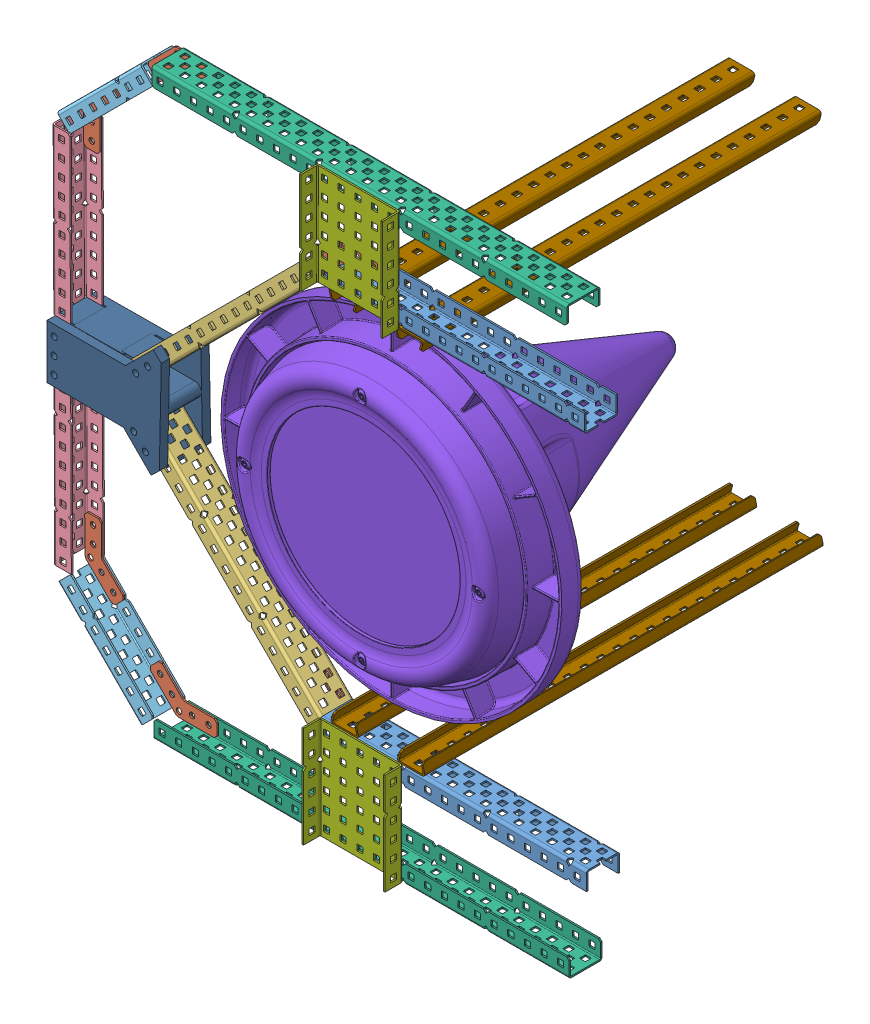
SolidWorks assembly Assem1, configuration Default. Lengths in mm.
Overall size (422.2 445.54 318.67).
23 component instances, 10 part files, 69 mates.
Components (placement in the parent):
- Channel 121-25 Aluminum-1: Channel 121-25 Aluminum [Default] at (-71.4802 130.2056 305.0856) size (203.98 13.87 25.4)
- 45 Degree Gusset Steel-1: 45 Degree Gusset Steel [Default] at (-111.3904 134.6957 291.8218) x (0.707107 0.707107 0) z (-0.707107 0.707107 0) size (29.13 1.17 50.81)
- Channel 121-15 Steel-1: Channel 121-15 Steel [Default] at (-213.9281 246.2136 305.0856) x (0.707107 -0.707107 0) z (0 0 1) size (190.5 13.87 25.4)
- Channel 121-25 Aluminum-5: Channel 121-25 Aluminum [Default] at (-72.9903 421.0087 299.2845) x (1 0 0) z (0 0 -1) size (203.98 13.87 25.4)
- 45 Degree Gusset Steel-11: 45 Degree Gusset Steel [Default] at (-112.9005 416.5439 290.6534) x (0.707107 -0.707107 0) z (-0.707107 -0.707107 0) size (29.13 1.17 50.81)
- Channel 121-15 Steel-5: Channel 121-15 Steel [Default] at (-215.4562 305.044 299.2845) x (0.707107 0.707107 0) z (0 0 -1) size (190.5 13.87 25.4)
- 45 Degree Gusset Steel-13: 45 Degree Gusset Steel [Default] at (-283.5405 116.115 290.6534) x (0.704273 0.70993 0) z (0.70993 -0.704273 0) size (29.13 1.17 50.81)
- 45 Degree Gusset Steel-14: 45 Degree Gusset Steel [Default] at (-284.8166 435.1532 291.8218) x (0.70993 -0.704273 0) z (0.704273 0.70993 0) size (29.13 1.17 50.81)
- Channel 121-23 Aluminum-1: Channel 121-23 Aluminum [Default] at (-300.7631 130.5564 305.0856) x (-0.004 0.999992 0) z (0 0 1) size (291.03 13.87 25.4)
- Channel 121-7 Aluminum-1: Channel 121-7 Aluminum [Default] at (-279.5913 449.3588 305.0856) x (0.707107 0.707107 0) z (0 0 1) size (89.86 13.87 25.4)
- Channel 121-7 Aluminum-4: Channel 121-7 Aluminum [Default] at (-252.8448 76.4391 305.0856) x (-0.707107 0.707107 0) z (0 0 1) size (89.86 13.87 25.4)
- 45 Degree Gusset Steel-15: 45 Degree Gusset Steel [Default] at (-212.4867 60.3556 290.6534) x (0 1 0) z (1 0 0) size (29.13 1.17 50.81)
- Channel 121-25 Al-1: Channel 121-25 Al [Default] at (66.0894 54.0056 305.0856) x (-1 0 0) z (0 0 1) size (317.5 13.87 25.4)
- Channel 121-25 Al-3: Channel 121-25 Al [Default] at (64.5793 497.2087 299.2845) x (-1 0 0) z (0 0 -1) size (317.5 13.87 25.4)
- 45 Degree Gusset Steel-17: 45 Degree Gusset Steel [Default] at (-213.7809 490.8587 291.8218) x (0 -1 0) z (1 0 0) size (29.13 1.17 50.81)
- Channel 151-6 Steel-1: Channel 151-6 Steel [Default] at (-82.0909 141.8404 316.0534) x (0 -1 0) z (1 0 0) size (77.37 13.87 63.5)
- Channel 151-6 Steel-2: Channel 151-6 Steel [Default] at (-51.8101 409.3739 316.0534) x (0 1 0) z (-1 0 0) size (77.37 13.87 63.5)
- mobileGoalPart-1: mobileGoalPart [Default] at (-61.7017 276.3928 324.2446) x (0.999695 0 -0.024681) z (0 1 0) size (254.67 244.72 254.67)
- rail-1: rail [Default] at (-78.8954 131.374 162.485) x (1 0 0) z (0 1 0) size (20.84 304.8 8.8)
- rail-2: rail [Default] at (-28.0954 131.374 162.485) x (1 0 0) z (0 1 0) size (20.84 304.8 8.8)
- rail-4: rail [Default] at (-29.6055 419.7384 162.485) x (-1 0 0) z (0 -1 0) size (20.84 304.8 8.8)
- rail-5: rail [Default] at (-80.4055 419.8403 162.485) x (-1 0 0) z (0 -1 0) size (20.84 304.8 8.8)
- Rear Frame Support^Assem1-1: Rear Frame Support^Assem1 [Default] at origin size (87.73 84.38 38.1) (virtual)
Mates (geometry in assembly coordinates):
- Coincident2: coincident anti-aligned: plane of Channel 121-25 Aluminum-1 through (-97.9454 130.2056 314.885) normal (0 -1 0); plane of 45 Degree Gusset Steel-1 through (-72.52 130.2056 290.6534) normal (0 1 0)
- Coincident3: coincident anti-aligned: plane of Channel 121-25 Aluminum-1 through (-97.9454 130.2056 290.6534) normal (0 0 1); plane of 45 Degree Gusset Steel-1 through (-124.8608 139.1858 290.6534) normal (0 0 -1)
- Distance1: distance = 2.286 mm: cylinder of 45 Degree Gusset Steel-1 through (-78.87 123.8556 290.6534) axis (0 0 1) radius 2.0701; plane of Channel 121-25 Aluminum-1 through (-76.584 126.167 289.485) normal (-1 0 0)
- Coincident7: coincident anti-aligned: plane of 45 Degree Gusset Steel-1 through (-97.92 130.2056 290.6534) normal (0.707107 0.707107 0); plane of Channel 121-15 Steel-1 through (-232.6418 264.9274 314.885) normal (-0.707107 -0.707107 0)
- Coincident8: coincident anti-aligned: plane of 45 Degree Gusset Steel-1 through (-124.8608 139.1858 290.6534) normal (0 0 -1); plane of Channel 121-15 Steel-1 through (-232.6418 264.9274 290.6534) normal (0 0 1)
- Distance2: distance = 2.286 mm: plane of Channel 121-15 Steel-1 through (-103.6494 130.2235 289.485) normal (-0.707107 0.707107 0); cylinder of 45 Degree Gusset Steel-1 through (-106.9003 130.2056 290.6534) axis (0 0 1) radius 2.0701
- Distance22: distance = 2.286 mm: cylinder of 45 Degree Gusset Steel-11 through (-117.3906 412.0538 291.8218) axis (0 0 -1) radius 2.0701; plane of Channel 121-15 Steel-5 through (-114.1577 412.0538 314.885) normal (-0.707107 -0.707107 0)
- Distance23: distance = 2.286 mm: cylinder of 45 Degree Gusset Steel-11 through (-117.3906 412.0538 291.8218) axis (0 0 -1) radius 2.0701; plane of Channel 121-15 Steel-5 through (-117.4266 408.785 314.885) normal (-0.707107 0.707107 0)
- Coincident40: coincident anti-aligned: plane of 45 Degree Gusset Steel-11 through (-126.3709 412.0538 290.6534) normal (0 0 -1); plane of Channel 121-15 Steel-5 through (-234.1699 286.3302 290.6534) normal (0 0 1)
- Coincident41: coincident anti-aligned: plane of Channel 121-25 Aluminum-5 through (-99.4555 421.0087 290.6534) normal (0 0 1); plane of 45 Degree Gusset Steel-11 through (-126.3709 412.0538 290.6534) normal (0 0 -1)
- Distance24: distance = 2.286 mm: plane of Channel 121-25 Aluminum-5 through (-78.0941 425.0473 314.885) normal (-1 0 0); cylinder of 45 Degree Gusset Steel-11 through (-80.3801 427.3841 291.8218) axis (0 0 -1) radius 2.0701
- Distance25: distance = 2.286 mm: cylinder of 45 Degree Gusset Steel-11 through (-80.3801 427.3841 291.8218) axis (0 0 -1) radius 2.0701; plane of Channel 121-25 Aluminum-5 through (-82.7169 429.6701 314.885) normal (0 -1 0)
- Distance26: distance = 2.286 mm: cylinder of 45 Degree Gusset Steel-13 through (-294.5106 148.5918 291.8218) axis (0 0 -1) radius 2.0701; plane of Channel 121-23 Aluminum-1 through (-296.7872 146.2458 289.485) normal (0.999992 0.004 0)
- Coincident48: coincident anti-aligned: plane of 45 Degree Gusset Steel-13 through (-278.9965 102.6627 290.6534) normal (0 0 -1); plane of Channel 121-23 Aluminum-1 through (-300.6572 104.0914 290.6534) normal (0 0 1)
- Parallel2: parallel anti-aligned: plane of 45 Degree Gusset Steel-13 through (-300.768 125.4245 291.8218) normal (-0.999992 -0.004 0); plane of Channel 121-23 Aluminum-1 through (-300.6572 104.0914 314.885) normal (0.999992 0.004 0)
- Distance27: distance = 2.286 mm: plane of Channel 121-23 Aluminum-1 through (-296.8057 150.8686 289.485) normal (0.004 -0.999992 0); cylinder of 45 Degree Gusset Steel-13 through (-294.5106 148.5918 291.8218) axis (0 0 -1) radius 2.0701
- Distance33: distance = 2.286 mm: cylinder of 45 Degree Gusset Steel-11 through (-108.4104 421.0341 291.8218) axis (0 0 -1) radius 2.0701; plane of Channel 121-15 Steel-5 through (-105.1775 421.0341 314.885) normal (-0.707107 -0.707107 0)
- Distance34: distance = 2.286 mm: plane of Channel 121-25 Aluminum-5 through (-90.7941 425.0473 314.885) normal (-1 0 0); cylinder of 45 Degree Gusset Steel-11 through (-93.0801 427.3841 291.8218) axis (0 0 -1) radius 2.0701
- Coincident54: coincident anti-aligned: plane of 45 Degree Gusset Steel-14 through (-280.3804 448.6414 290.6534) normal (0 0 -1); plane of Channel 121-23 Aluminum-1 through (-300.6572 104.0914 290.6534) normal (0 0 1)
- Distance36: distance = 2.286 mm: plane of Channel 121-23 Aluminum-1 through (-297.8032 400.2438 289.485) normal (0.999992 0.004 0); cylinder of 45 Degree Gusset Steel-14 through (-295.5266 402.5897 290.6534) axis (0 0 1) radius 2.0701
- Distance37: distance = 2.286 mm: cylinder of 45 Degree Gusset Steel-14 through (-295.5266 402.5897 290.6534) axis (0 0 1) radius 2.0701; plane of Channel 121-23 Aluminum-1 through (-297.8217 404.8666 289.485) normal (0.004 -0.999992 0)
- Distance40: distance = 2.286 mm: cylinder of 45 Degree Gusset Steel-14 through (-295.5774 415.2896 290.6534) axis (0 0 1) radius 2.0701; plane of Channel 121-23 Aluminum-1 through (-297.854 412.9437 289.485) normal (0.999992 0.004 0)
- Coincident55: coincident anti-aligned: plane of 45 Degree Gusset Steel-14 through (-280.3804 448.6414 290.6534) normal (0 0 -1); plane of Channel 121-7 Aluminum-1 through (-298.305 430.6451 290.6534) normal (0 0 1)
- Distance42: distance = 2.286 mm: plane of Channel 121-7 Aluminum-1 through (-283.6133 439.6253 289.485) normal (0.707107 -0.707107 0); cylinder of 45 Degree Gusset Steel-14 through (-280.3445 439.6613 290.6534) axis (0 0 1) radius 2.0701
- Distance43: distance = 2.286 mm: plane of Channel 121-7 Aluminum-1 through (-280.3445 442.8941 289.485) normal (-0.707107 -0.707107 0); cylinder of 45 Degree Gusset Steel-14 through (-280.3445 439.6613 290.6534) axis (0 0 1) radius 2.0701
- Distance45: distance = 2.286 mm: plane of Channel 121-7 Aluminum-1 through (-289.3248 427.3763 289.485) normal (-0.707107 0.707107 0); cylinder of 45 Degree Gusset Steel-14 through (-289.2888 430.6452 290.6534) axis (0 0 1) radius 2.0701
- Coincident58: coincident anti-aligned: plane of 45 Degree Gusset Steel-13 through (-278.9965 102.6627 290.6534) normal (0 0 -1); plane of Channel 121-7 Aluminum-4 through (-234.1311 57.7253 290.6534) normal (0 0 1)
- Distance55: distance = 2.286 mm: plane of Channel 121-7 Aluminum-4 through (-288.0126 117.3183 289.485) normal (0.707107 0.707107 0); cylinder of 45 Degree Gusset Steel-13 through (-288.0485 120.5871 291.8218) axis (0 0 -1) radius 2.0701
- Distance56: distance = 2.286 mm: plane of Channel 121-7 Aluminum-4 through (-291.2814 120.5871 289.485) normal (0.707107 -0.707107 0); cylinder of 45 Degree Gusset Steel-13 through (-288.0485 120.5871 291.8218) axis (0 0 -1) radius 2.0701
- Distance57: distance = 2.286 mm: cylinder of 45 Degree Gusset Steel-13 through (-279.0324 111.6429 291.8218) axis (0 0 -1) radius 2.0701; plane of Channel 121-7 Aluminum-4 through (-275.7635 111.6069 289.485) normal (-0.707107 -0.707107 0)
- Coincident61: coincident anti-aligned: plane of Channel 121-7 Aluminum-4 through (-234.1311 57.7253 290.6534) normal (0 0 1); plane of 45 Degree Gusset Steel-15 through (-199.7867 54.0056 290.6534) normal (0 0 -1)
- Distance58: distance = 2.286 mm: cylinder of 45 Degree Gusset Steel-15 through (-243.1472 75.6858 291.8218) axis (0 0 -1) radius 2.0701; plane of Channel 121-7 Aluminum-4 through (-246.3801 75.6858 289.485) normal (0.707107 -0.707107 0)
- Distance60: distance = 2.286 mm: plane of Channel 121-7 Aluminum-4 through (-243.1113 72.417 289.485) normal (0.707107 0.707107 0); cylinder of 45 Degree Gusset Steel-15 through (-243.1472 75.6858 291.8218) axis (0 0 -1) radius 2.0701
- Distance61: distance = 2.286 mm: cylinder of 45 Degree Gusset Steel-15 through (-234.167 66.7056 291.8218) axis (0 0 -1) radius 2.0701; plane of Channel 121-7 Aluminum-4 through (-234.1311 63.4368 289.485) normal (0.707107 0.707107 0)
- Coincident63: coincident anti-aligned: plane of 45 Degree Gusset Steel-15 through (-225.1867 54.0056 291.8218) normal (0 -1 0); plane of Channel 121-25 Al-1 through (92.5546 54.0056 314.885) normal (0 1 0)
- Coincident64: coincident anti-aligned: plane of 45 Degree Gusset Steel-15 through (-199.7867 54.0056 290.6534) normal (0 0 -1); plane of Channel 121-25 Al-1 through (92.5546 54.0056 290.6534) normal (0 0 1)
- Tangent25: tangent anti-aligned: cylinder of 45 Degree Gusset Steel-15 through (-218.8367 60.3556 291.8218) axis (0 0 -1) radius 2.0701; plane of Channel 121-25 Al-1 through (-220.9068 58.0442 289.485) normal (1 0 0)
- Coincident65: coincident anti-aligned: plane of Channel 121-25 Aluminum-1 through (-97.9454 130.2056 314.885) normal (0 0 1); plane of Channel 151-6 Steel-1 through (-34.1914 168.3056 314.885) normal (0 0 -1)
- Coincident66: coincident aligned: plane of Channel 121-25 Al-1 through (-93.9068 58.0442 289.485) normal (1 0 0); plane of Channel 151-6 Steel-1 through (-93.9068 62.667 317.425) normal (1 0 0)
- Coincident67: coincident aligned: plane of Channel 121-25 Al-1 through (-89.284 58.0442 289.485) normal (0 1 0); plane of Channel 151-6 Steel-1 through (-93.9068 58.0442 317.425) normal (0 1 0)
- Coincident68: coincident anti-aligned: plane of Channel 121-25 Al-1 through (92.5546 54.0056 314.885) normal (0 0 1); plane of Channel 151-6 Steel-1 through (-34.1914 168.3056 314.885) normal (0 0 -1)
- Symmetric1: symmetric aligned: plane of Channel 121-25 Aluminum-5 through (-31.9169 429.6701 314.885) normal (0 -1 0); plane of Channel 151-6 Steel-2 through (-39.9941 429.6701 317.425) normal (0 -1 0); plane of Channel 151-6 Steel-2 through (-99.7095 382.9087 316.0534) normal (0 0 1)
- Coincident74: coincident aligned: plane of Channel 121-25 Al-3 through (-78.0941 493.1701 314.885) normal (-1 0 0); plane of Channel 151-6 Steel-2 through (-78.0941 488.5473 317.425) normal (-1 0 0)
- Coincident75: coincident anti-aligned: plane of Channel 121-25 Al-3 through (91.0445 497.2087 314.885) normal (0 0 1); plane of Channel 151-6 Steel-2 through (-99.7095 382.9087 314.885) normal (0 0 -1)
- Coincident76: coincident aligned: plane of Channel 121-25 Al-3 through (-78.0941 488.5473 314.885) normal (0 1 0); plane of Channel 151-6 Steel-2 through (-78.0941 488.5473 317.425) normal (0 1 0)
- Coincident80: coincident anti-aligned: plane of Channel 121-25 Al-3 through (91.0445 497.2087 289.485) normal (0 -1 0); plane of 45 Degree Gusset Steel-17 through (-226.4809 497.2087 290.6534) normal (0 1 0)
- Coincident81: coincident anti-aligned: plane of Channel 121-25 Al-3 through (91.0445 497.2087 290.6534) normal (0 0 1); plane of 45 Degree Gusset Steel-17 through (-201.0809 497.2087 290.6534) normal (0 0 -1)
- Distance65: distance = 2.286 mm anti-aligned: cylinder of 45 Degree Gusset Steel-17 through (-220.1309 490.8587 290.6534) axis (0 0 1) radius 2.0701; plane of Channel 121-25 Al-3 through (-222.4169 493.1701 314.885) normal (1 0 0)
- Coincident95: coincident aligned: plane of Channel 121-25 Aluminum-1 through (-51.184 126.167 289.485) normal (-1 0 0); plane of Channel 151-6 Steel-1 through (-51.184 126.167 317.425) normal (-1 0 0)
- Coincident96: coincident aligned: plane of Channel 121-25 Aluminum-1 through (-55.8068 126.167 289.485) normal (0 -1 0); plane of Channel 151-6 Steel-1 through (-55.8068 126.167 317.425) normal (0 -1 0)
- Coincident97: coincident aligned: plane of Channel 121-25 Aluminum-5 through (-39.9941 425.0473 314.885) normal (-1 0 0); plane of Channel 151-6 Steel-2 through (-39.9941 425.0473 317.425) normal (-1 0 0)
- Coincident98: coincident aligned: plane of Channel 121-25 Aluminum-5 through (-44.6169 425.0473 314.885) normal (0 1 0); plane of Channel 151-6 Steel-2 through (-39.9941 425.0473 317.425) normal (0 1 0)
- Tangent37: tangent anti-aligned: plane of Channel 121-15 Steel-1 through (-231.8156 265.7536 314.885) normal (0.707107 0.707107 0); cone of mobileGoalPart-1 through (-62.407 276.3928 295.6783) axis (-0.024681 0 -0.999695)
- Tangent38: tangent anti-aligned: plane of Channel 121-15 Steel-5 through (-233.3437 285.504 289.485) normal (0.707107 -0.707107 0); cone of mobileGoalPart-1 through (-62.407 276.3928 295.6783) axis (-0.024681 0 -0.999695)
- Distance72: distance = 2.286 mm: cylinder of 45 Degree Gusset Steel-17 through (-244.4414 475.5284 290.6534) axis (0 0 1) radius 2.0701; plane of Channel 121-7 Aluminum-1 through (-247.6923 475.5464 289.485) normal (0.707107 0.707107 0)
- Coincident100: coincident anti-aligned: plane of Channel 121-7 Aluminum-1 through (-298.305 430.6451 314.885) normal (0.707107 -0.707107 0); plane of 45 Degree Gusset Steel-17 through (-232.5676 496.3824 290.6534) normal (-0.707107 0.707107 0)
- Coincident101: coincident anti-aligned: plane of Channel 121-7 Aluminum-1 through (-298.305 430.6451 290.6534) normal (0 0 1); plane of 45 Degree Gusset Steel-17 through (-201.0809 497.2087 290.6534) normal (0 0 -1)
- Coincident102: coincident anti-aligned: plane of Channel 121-25 Aluminum-5 through (-99.4555 421.0087 314.885) normal (0 0 1); plane of Channel 151-6 Steel-2 through (-99.7095 382.9087 314.885) normal (0 0 -1)
- Coincident103: coincident anti-aligned: plane of Channel 121-25 Aluminum-1 through (-97.9454 131.374 314.885) normal (0 1 0); plane of rail-1 through (-88.4204 131.374 314.885) normal (0 -1 0)
- Coincident104: coincident aligned: plane of Channel 121-25 Aluminum-1 through (-81.2068 128.834 310.8464) normal (0 0 -1); plane of rail-1 through (-80.6988 131.374 310.8464) normal (0 0 -1)
- Coincident105: coincident aligned: plane of Channel 121-25 Aluminum-1 through (-81.2068 128.834 306.2236) normal (1 0 0); plane of rail-1 through (-81.2068 131.374 310.3384) normal (1 0 0)
- Coincident106: coincident anti-aligned: plane of Channel 121-25 Aluminum-1 through (-97.9454 131.374 314.885) normal (0 1 0); plane of rail-2 through (-37.6204 131.374 314.885) normal (0 -1 0)
- Coincident107: coincident aligned: plane of Channel 121-25 Aluminum-1 through (-17.7068 128.834 310.8464) normal (0 0 -1); plane of rail-2 through (-29.8988 131.374 310.8464) normal (0 0 -1)
- Coincident111: coincident aligned: plane of Channel 121-25 Aluminum-1 through (-30.4068 128.834 306.2236) normal (1 0 0); plane of rail-2 through (-30.4068 131.374 310.3384) normal (1 0 0)
- Coincident112: coincident anti-aligned: plane of Channel 121-25 Aluminum-5 through (-99.4555 419.8403 289.485) normal (0 -1 0); plane of rail-5 through (-70.8805 419.8403 314.885) normal (0 1 0)
- Coincident113: coincident aligned: plane of Channel 121-25 Aluminum-5 through (-78.0941 422.3803 310.8464) normal (-1 0 0); plane of rail-5 through (-78.0941 419.8403 310.3384) normal (-1 0 0)
- Coincident114: coincident aligned: plane of Channel 121-25 Aluminum-5 through (-82.7169 422.3803 310.8464) normal (0 0 -1); plane of rail-5 through (-78.6021 419.8403 310.8464) normal (0 0 -1)
- Coincident115: coincident aligned: plane of Channel 121-25 Aluminum-5 through (-31.9169 422.3803 310.8464) normal (0 0 -1); plane of rail-4 through (-27.8021 419.7384 310.8464) normal (0 0 -1)
- Coincident116: coincident aligned: plane of Channel 121-25 Aluminum-5 through (-31.9169 422.3803 310.8464) normal (1 0 0); plane of rail-4 through (-31.9169 419.7384 310.3384) normal (1 0 0)
